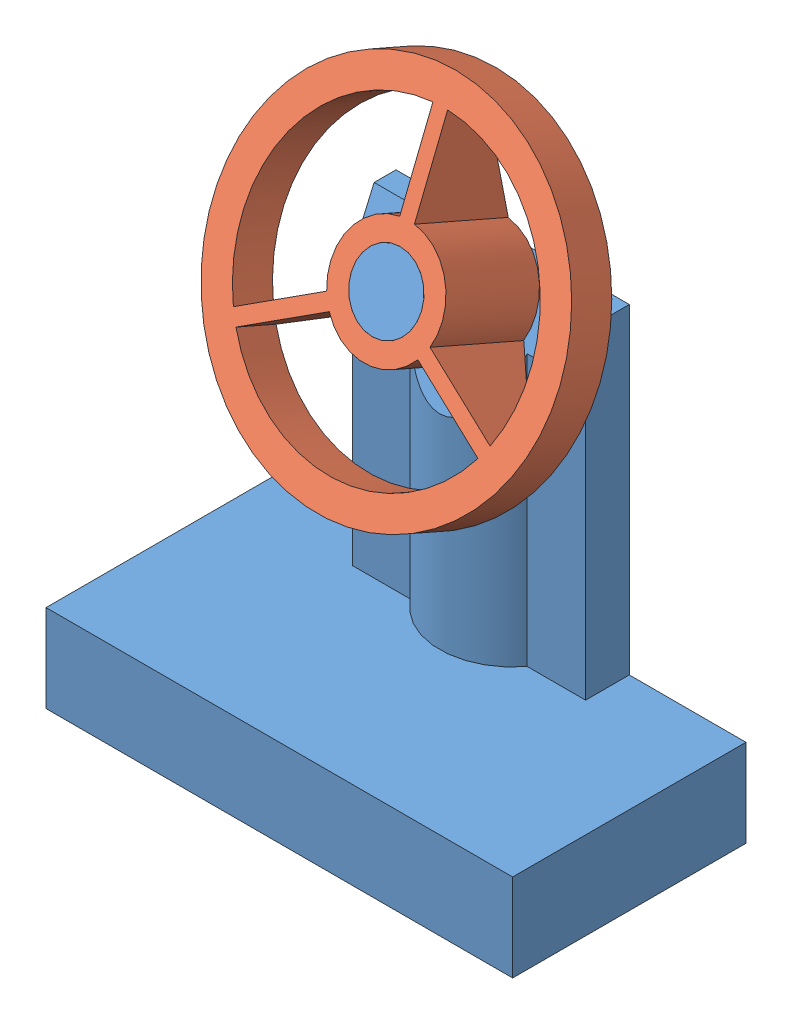
SolidWorks assembly Assem1, configuration Default. Lengths in mm.
Overall size (16 20.07 9.29).
2 component instances, 2 part files, 2 mates.
Components (placement in the parent):
- SteeringWheel-1: SteeringWheel [Default] at origin size (16 15.65 8)
- Steering_Wheel-2: Steering_Wheel [Default] at (8 13.1429 -6.875) x (0.999744 0.020734 -0.009071) z (0 0.400819 0.916157) size (11.8 11.8 3.5)
Mates (geometry in assembly coordinates):
- Concentric5: concentric aligned: cylinder of SteeringWheel-1 through (8 14.5457 -3.6684) axis (0 -0.400819 -0.916157) radius 1.2; cylinder of Steering_Wheel-2 through (8 14.5457 -3.6684) axis (0 -0.400819 -0.916157) radius 1.2
- Coincident1: coincident anti-aligned: plane of SteeringWheel-1 through (1 10 -5.5) normal (0 0.400819 0.916157); plane of Steering_Wheel-2 through (8 13.1429 -6.875) normal (0 -0.400819 -0.916157)
